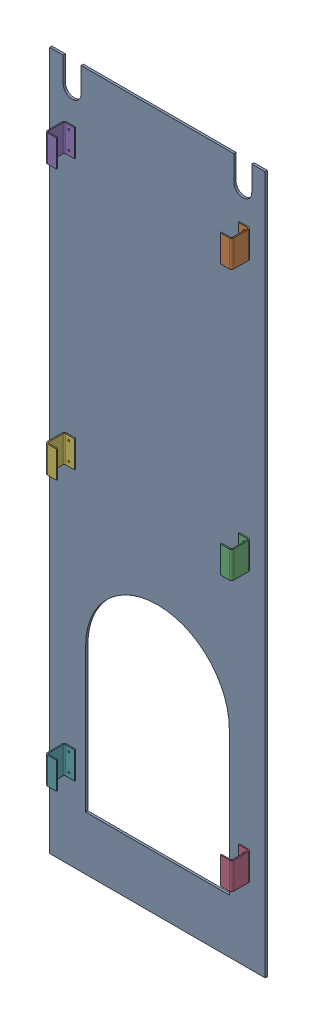
SolidWorks assembly GE-16068_ASM, configuration Default. Lengths in mm.
Overall size (609.6 1974.85 60.33).
7 component instances, 2 part files, 0 mates.
Components (placement in the parent):
- GE-16069-1: GE-16069 [Default] at origin size (609.6 1974.85 6.35)
- GE-16070-1: GE-16070 [Default] at (263.525 752.475 6.35) x (0 0 -1) z (1 0 0) size (53.98 76.2 31.75)
- GE-16070-2: GE-16070 [Default] at (263.525 -9.525 6.35) x (0 0 -1) z (1 0 0) size (53.98 76.2 31.75)
- GE-16070-3: GE-16070 [Default] at (263.525 -771.525 6.35) x (0 0 -1) z (1 0 0) size (53.98 76.2 31.75)
- GE-16070-4: GE-16070 [Default] at (-263.525 828.675 6.35) x (0 0 -1) z (-1 0 0) size (53.98 76.2 31.75)
- GE-16070-5: GE-16070 [Default] at (-263.525 66.675 6.35) x (0 0 -1) z (-1 0 0) size (53.98 76.2 31.75)
- GE-16070-6: GE-16070 [Default] at (-263.525 -695.325 6.35) x (0 0 -1) z (-1 0 0) size (53.98 76.2 31.75)
